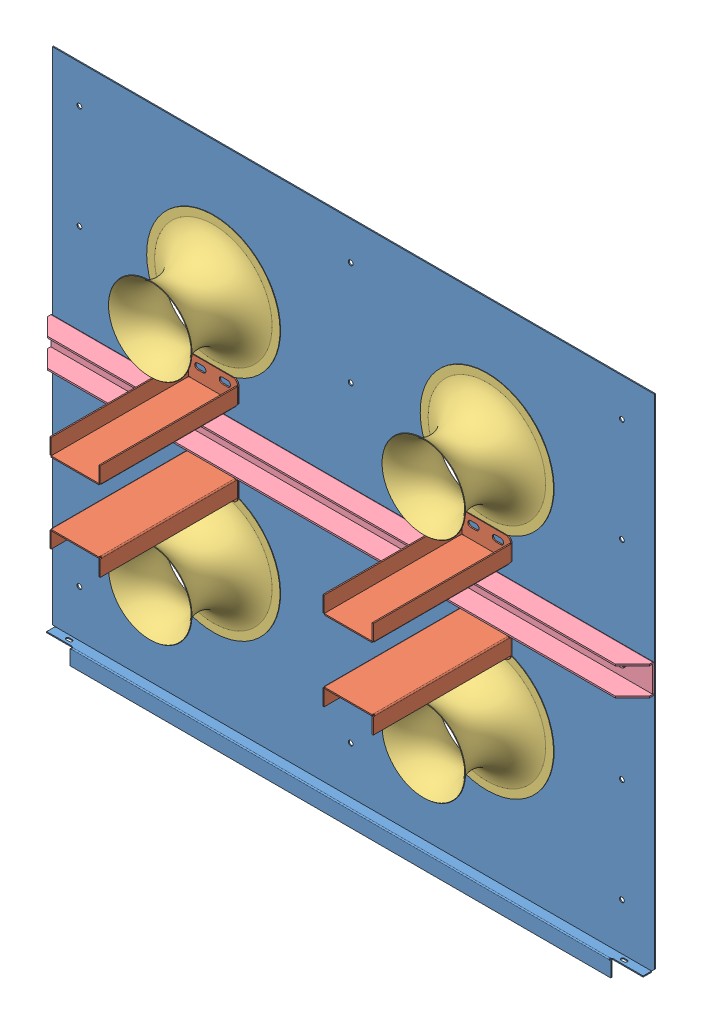
SolidWorks assembly 濾材風箱-1, configuration 預設. Lengths in mm.
Overall size (1128.4 969.2 262.16).
10 component instances, 4 part files, 7 mates.
Components (placement in the parent):
- LB-A54A-02-11-1: LB-A54A-02-11 [預設] at (-609.5195 -443.3362 -10.75) size (1128.4 969.2 21.5)
- LB-A54-07-4-1: LB-A54-07-4 [預設] at (-382.2595 134.0628 -46.99) x (0 0 1) z (0 1 0) size (260.16 94.4 42.16)
- LB-A54-07-4-2: LB-A54-07-4 [預設] at (129.7405 134.0628 -46.99) x (0 0 1) z (0 1 0) size (260.16 94.4 42.16)
- LB-A54-07-4-3: LB-A54-07-4 [預設] at (-231.4595 17.0628 -46.99) x (0 0 1) z (0 -1 0) size (260.16 94.4 42.16)
- LB-A54-07-4-4: LB-A54-07-4 [預設] at (280.5405 17.0628 -46.99) x (0 0 1) z (0 -1 0) size (260.16 94.4 42.16)
- 250文氏管-1: 250文氏管 [預設] at (-422.6898 248.1172 -8.75) x (0.927762 0.373172 0) z (0.373172 -0.927762 0) size (250 120 250)
- 250文氏管-2: 250文氏管 [預設] at (90.1102 248.1172 -8.75) x (0.927762 0.373172 0) z (0.373172 -0.927762 0) size (250 120 250)
- 250文氏管-3: 250文氏管 [預設] at (-422.6898 -178.8828 -8.75) x (0.927762 0.373172 0) z (0.373172 -0.927762 0) size (250 120 250)
- 250文氏管-4: 250文氏管 [預設] at (90.1102 -178.8828 -8.75) x (0.927762 0.373172 0) z (0.373172 -0.927762 0) size (250 120 250)
- LB-A54A-02-12-2: LB-A54A-02-12 [預設] at (-84291.9278 16147.3106 -8.75) size (1128.4 55 40.99)
Mates (geometry in assembly coordinates):
- 重合/共線/共點6: coincident aligned: plane of LB-A54-07-4-1 through (-354.0195 53.6228 -36.99) normal (-1 0 0); plane of LB-A54-07-4-3 through (-354.0195 23.1028 -36.99) normal (-1 0 0)
- 平行相距2: distance = 117 mm anti-aligned: plane of LB-A54-07-4-1 through (-269.6595 134.0628 -36.99) normal (0 -1 0); plane of LB-A54-07-4-3 through (-344.0595 17.0628 -36.99) normal (0 1 0)
- 重合/共線/共點7: coincident anti-aligned: plane of LB-A54A-02-11-1 through (510.8805 -396.9362 -8.75) normal (0 0 1); plane of LB-A54A-02-12-2 through (549.3805 80.4638 -8.75) normal (0 0 -1)
- 同軸心1: concentric aligned: cylinder of LB-A54A-02-11-1 through (458.1805 80.4638 -8.75) axis (0 0 -1) radius 4.5; cylinder of LB-A54A-02-12-2 through (458.1805 80.4638 -5.75) axis (0 0 -1) radius 11
- 同軸心2: concentric aligned: cylinder of LB-A54A-02-11-1 through (-50.3195 80.4638 -8.75) axis (0 0 -1) radius 4.5; cylinder of LB-A54A-02-12-2 through (-50.3195 80.4638 -5.75) axis (0 0 -1) radius 11
- 局部直線複製2: unknown: line of LB-A54A-02-11-1 through (518.8805 541.7638 -8.75) axis (-1 0 0)
- 局部直線複製3: unknown: line of LB-A54A-02-11-1 through (518.8805 541.7638 -8.75) axis (-1 0 0); line of LB-A54A-02-11-1 through (-609.5195 541.7638 -8.75) axis (0 -1 0)
